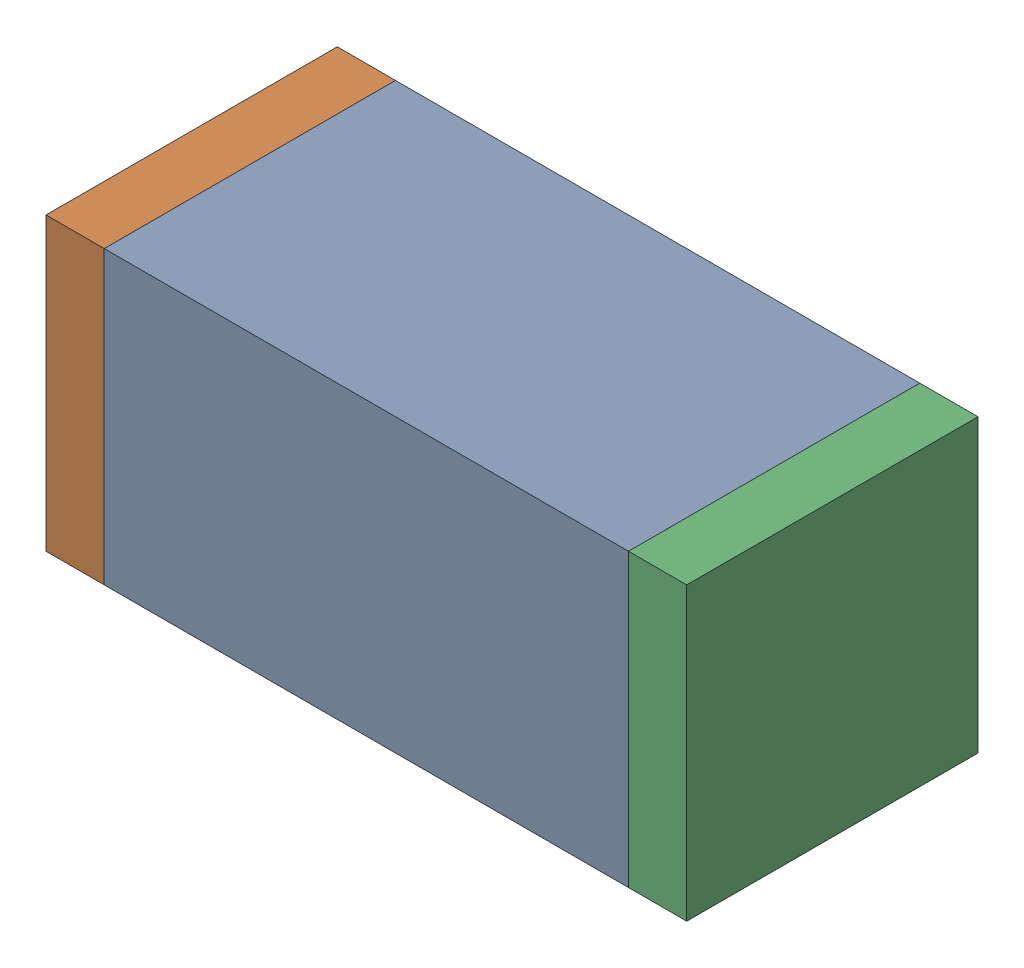
SolidWorks assembly R43, configuration Default. Lengths in mm.
Overall size (1.1 0.5 0.5).
6 component instances, 2 part files, 0 mates.
Components (placement in the parent):
- 836749680-1: 836749680 [Default] at (120.4 53.5 0) size (0.9 0.5 0.5)
  - Extruded_4-1: Extruded_4 [Default] at origin size (0.9 0.5 0.5)
- 810156080-1: 810156080 [Default] at (119.9 53.5 0) size (0.1 0.5 0.5)
  - Extruded_5-1: Extruded_5 [Default] at origin size (0.1 0.5 0.5)
- 810156080-2: 810156080 [Default] at (120.9 53.5 0) size (0.1 0.5 0.5)
  - Extruded_5-1: Extruded_5 [Default] at origin size (0.1 0.5 0.5)
